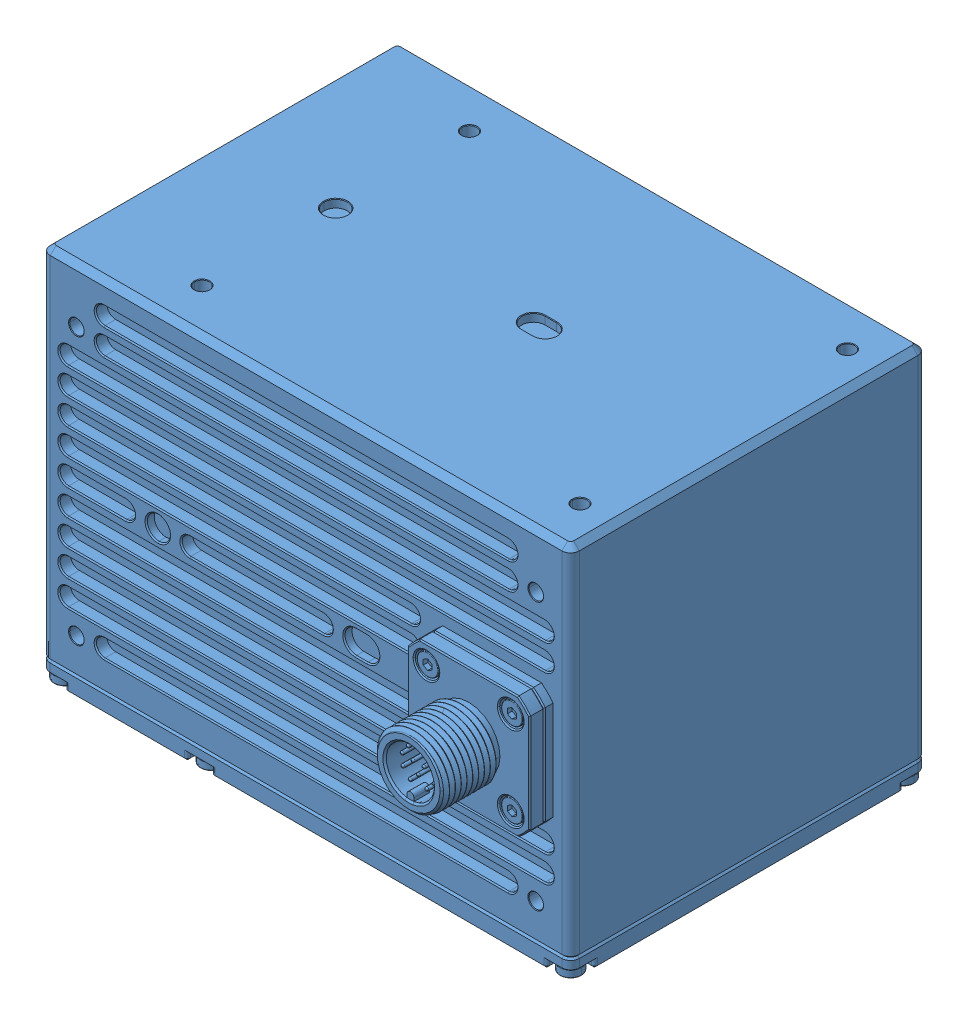
SolidWorks assembly AVIA, configuration Default. Lengths in mm.
Overall size (91.02 64.8 76.07).
3 component instances, 2 part files, 0 mates.
Components (placement in the parent):
- Livox_Avia_shell_FOV.stp-1: Livox_Avia_shell_FOV.stp [Default] at origin size (1207.64 1420.81 1420.81)
  - LIVOX_AVIA.stp-1: LIVOX_AVIA.stp [Default] at origin size (91.02 64.8 76.07)
  - LIVOX_AVIA_FOV.stp-1: LIVOX_AVIA_FOV.stp [Default] at (19.97 48.3 -38.5) x (0 0 -1) z (1 0 0) size (1420.81 1420.81 1123.13) (hidden)
